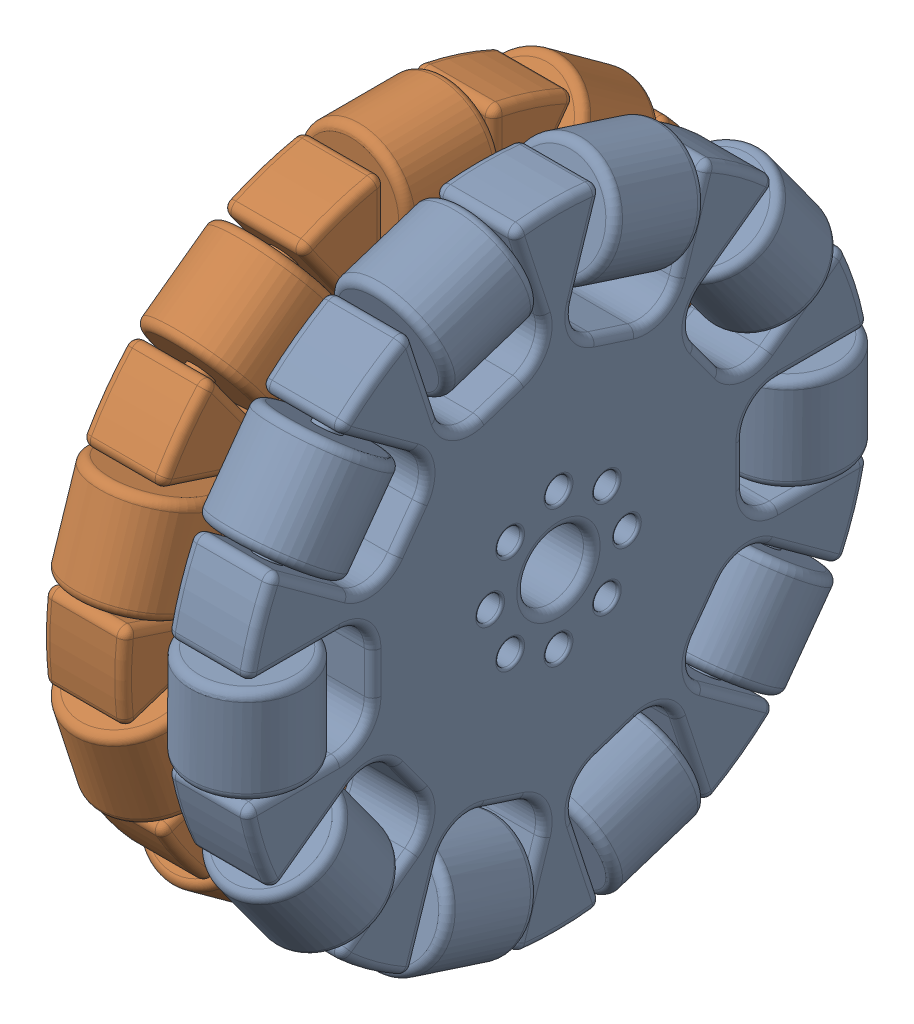
SolidWorks assembly dualOmniWheel, configuration Default. Lengths in mm.
Overall size (27.8 78.5 78.5).
2 component instances, 1 part files, 5 mates.
Components (placement in the parent):
- singleOmniWheel-1: singleOmniWheel [Default] at (7.15 0 0) x (1 0 0) z (0 1 0) size (13.5 78.5 77.69)
- singleOmniWheel-2: singleOmniWheel [Default] at (-7.15 0 0) size (13.5 78.5 77.69)
Mates (geometry in assembly coordinates):
- Concentric1: concentric aligned: cylinder of singleOmniWheel-1 through (12.05 0 0) axis (-1 0 0) radius 4; cylinder of singleOmniWheel-2 through (-2.25 0 0) axis (-1 0 0) radius 4
- Concentric3: concentric aligned: cylinder of singleOmniWheel-1 through (0.4 8.2125 0) axis (1 0 0) radius 1.4375; cylinder of singleOmniWheel-2 through (-12.05 8.2125 0) axis (1 0 0) radius 1.4375
- Distance3: distance = 2.25 mm: plane of assembly through (0 0 0) normal (1 0 0); plane of assembly; plane of singleOmniWheel-1 through (2.25 0 0) normal (-1 0 0)
- Concentric6: concentric anti-aligned: cylinder of singleOmniWheel-2 through (-2.25 0 0) axis (-1 0 0) radius 4
- Distance7: distance = 2.25 mm: plane of assembly through (0 0 0) normal (1 0 0); plane of assembly; plane of singleOmniWheel-2 through (-2.25 0 0) normal (1 0 0)
